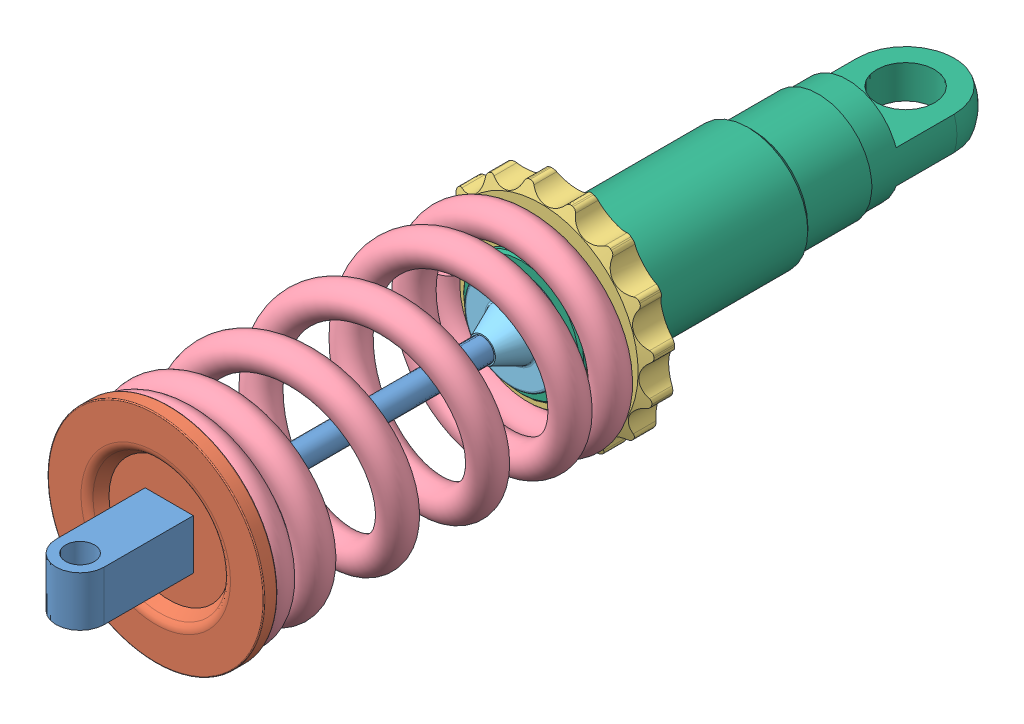
SolidWorks assembly suspension, configuration Default. Lengths in mm.
Overall size (24.15 24.15 93.48).
6 component instances, 6 part files, 38 mates.
Components (placement in the parent):
- Steblo-1: Steblo [Default] at (-24.7525 22.657 64.8138) x (-1 0 0) z (0 1 0) size (5 44.25 5.17)
- shaiba-1: shaiba [Default] at (-24.7525 21.7945 55.5638) x (0.996888 0.07883 0) z (0.07883 -0.996888 0) size (22.45 2.8 22.45)
- gaika-1: gaika [Default] at (-24.7525 21.7945 26.718) x (0.998753 -0.049919 0) z (-0.049919 -0.998753 0) size (22.31 5.02 22.31)
- Prujina-1: Prujina [Default] at (-25.0887 21.6429 17.0138) size (22.62 22.35 41.82)
- Manshon-3: Manshon [Default] at (-24.7525 21.7945 24.8648) x (0.406607 0.913603 0) z (0.913603 -0.406607 0) size (10 4.03 10)
- Cilinder-2: Cilinder [Default] at (-24.7525 21.7945 -26.1618) size (12.45 12.45 45.2)
Mates (geometry in assembly coordinates):
- Concentric1: concentric aligned: cylinder of Cilinder-1 through (-24.6568 29.4468 -39.4946) axis (0 0 1) radius 5; cylinder of Steblo-1 through (-24.7525 21.7945 23.0638) axis (0 0 1) radius 1.203
- Concentric3: concentric aligned: cylinder of Cilinder-1 through (-24.6568 29.4468 -39.4946) axis (0 0 1) radius 5; cylinder of Manshon-1 through (-24.6568 29.4468 33.4722) axis (0 0 1) radius 5
- Coincident1: coincident aligned: plane of Cilinder-1 through (-24.6568 29.4468 -6.9946) normal (0 0 1); plane of Manshon-1 through (-19.9068 29.4468 -6.9946) normal (0 0 1)
- Coincident2: coincident anti-aligned: plane of Steblo-1 through (-22.2525 19.207 55.5638) normal (0 0 -1); plane of shaiba-1 through (-22.2603 21.9916 55.5638) normal (0 0 1)
- Concentric4: concentric aligned: cylinder of Steblo-1 through (-24.7525 21.7945 23.0638) axis (0 0 1) radius 1.203; cylinder of shaiba-1 through (-24.7525 21.7945 67.1029) axis (0 0 1) radius 2.5
- Concentric5: concentric anti-aligned: cylinder of Cilinder-1 through (-24.6568 29.4468 -6.9946) axis (0 0 -1) radius 6.225; cylinder of gaika-1 through (-24.7525 21.7945 68.5253) axis (0 0 1) radius 5.875
- Coincident3: coincident aligned: plane of Cilinder-1 through (-24.6568 29.4468 -52.1946) normal (0 1 0); plane of Prujina-1 through (-25.0887 21.6429 17.0138) normal (0 1 0)
- Coincident4: coincident aligned: plane of Cilinder-1 through (-24.6568 29.4468 -52.1946) normal (1 0 0); plane of Prujina-1 through (-25.0887 21.6429 17.0138) normal (1 0 0)
- Coincident5: coincident anti-aligned: plane of shaiba-1 through (-16.8189 22.4219 55.5638) normal (0 0 -1); plane of Prujina-1 through (-36.1151 -3.957 55.5638) normal (0 0 1)
- Coincident6: coincident anti-aligned: plane of gaika-1 through (-17.6364 21.4389 17.0138) normal (0 0 1); plane of Prujina-1 through (-36.1151 50.6797 17.0138) normal (0 0 -1)
- Concentric6: concentric anti-aligned: cylinder of ? through (-24.6568 -16.8282 -46.8696) axis (0 1 0) radius 3; cylinder of ? through (-24.6568 32.9718 -46.8696) axis (0 -1 0) radius 3
- Coincident7: coincident anti-aligned: plane of ? through (23.3432 31.1718 -54.4198) normal (0 1 0); plane of ? through (-24.6568 36.3468 -41.5446) normal (0 -1 0)
- Concentric7: concentric: cylinder of ? through (-24.6568 32.9718 -46.8696) axis (0 -1 0) radius 2.5; cylinder of ? through (-24.6568 25.9218 -46.8696) axis (0 1 0) radius 3
- Coincident8: coincident anti-aligned: plane of ? through (23.3432 27.7218 -54.4198) normal (0 -1 0); plane of ? through (-24.6568 22.5468 -41.5446) normal (0 1 0)
- Concentric8: concentric aligned: cylinder of Steblo-1 through (-24.7525 19.207 64.8138) axis (0 -1 0) radius 1.5; cylinder of plastmasova vtulka-3 through (-24.6568 32.9718 47.6054) axis (0 -1 0) radius 3
- Coincident9: coincident anti-aligned: plane of Steblo-1 through (-24.7525 24.382 64.8138) normal (0 1 0); plane of ? through (-24.6568 36.3468 103.4554) normal (0 -1 0)
- Concentric9: concentric anti-aligned: cylinder of Steblo-1 through (-24.7525 19.207 64.8138) axis (0 -1 0) radius 1.5; cylinder of plastmasova vtulka-4 through (-24.6568 25.9218 47.6054) axis (0 1 0) radius 3
- Coincident10: coincident anti-aligned: plane of Steblo-1 through (-24.7525 19.207 64.8138) normal (0 -1 0); plane of ? through (-24.6568 22.5468 103.4554) normal (0 1 0)
- Concentric10: concentric anti-aligned: cylinder of plastmasova vtulka-2 through (-24.6568 25.9218 -46.8696) axis (0 1 0) radius 2.5; cylinder of Vtulka na ushite-2 through (-24.6568 29.6968 -46.8696) axis (0 -1 0) radius 2.5
- Coincident11: coincident: plane of ? through (-24.6568 17.5468 -41.5446) normal (0 -1 0); plane of ? through (-24.6568 17.5468 -41.5446) normal (0 -1 0)
- Concentric11: concentric anti-aligned: cylinder of plastmasova vtulka-3 through (-24.6568 32.9718 47.6054) axis (0 -1 0) radius 2.5; cylinder of Vtulka na ushite-1 through (-24.6568 29.1968 47.6054) axis (0 1 0) radius 2.5
- Coincident12: coincident: plane of ? through (-24.6568 41.3468 103.4554) normal (0 1 0); plane of ? through (-24.6568 41.3468 103.4554) normal (0 1 0)
- Concentric13: concentric anti-aligned: cylinder of fasonna gaika-2 through (-24.6568 44.1968 47.6054) axis (0 -1 0) radius 3.9; cylinder of fasonen bolt-2 through (-24.6568 14.6968 47.6054) axis (0 1 0) radius 3
- Coincident15: coincident anti-aligned: plane of fasonna gaika-2 through (-24.6568 14.6968 47.6054) normal (0 -1 0); plane of fasonen bolt-2 through (-24.6568 14.6968 47.6054) normal (0 1 0)
- Concentric14: concentric anti-aligned: cylinder of fasonen bolt-1 through (-24.6568 44.1968 -46.8696) axis (0 -1 0) radius 3; cylinder of fasonna gaika-1 through (-24.6568 14.6968 -46.8696) axis (0 1 0) radius 3.9
- Coincident16: coincident anti-aligned: plane of fasonen bolt-1 through (-24.6568 44.1968 -46.8696) normal (0 -1 0); plane of fasonna gaika-1 through (-24.6568 44.1968 -46.8696) normal (0 1 0)
- Concentric15: concentric anti-aligned: cylinder of Vtulka na ushite-2 through (-24.6568 29.6968 -46.8696) axis (0 -1 0) radius 2; cylinder of fasonna gaika-1 through (-24.6568 14.6968 -46.8696) axis (0 1 0) radius 3.9
- Concentric16: concentric anti-aligned: cylinder of Vtulka na ushite-1 through (-24.6568 29.1968 47.6054) axis (0 1 0) radius 2; cylinder of fasonna gaika-2 through (-24.6568 44.1968 47.6054) axis (0 -1 0) radius 3.9
- Distance3: distance = 2.85 mm anti-aligned: plane of ? through (-24.6568 44.1968 47.6054) normal (0 -1 0); plane of ? through (-24.6568 41.3468 103.4554) normal (0 1 0)
- Distance4: distance = 2.85 mm: plane of ? through (-24.6568 17.5468 -41.5446) normal (0 -1 0); plane of ? through (-24.6568 14.6968 -41.5446) normal (0 1 0)
- Distance8: distance = 43.95 mm anti-aligned: plane of Cilinder-1 through (-24.6568 29.4468 -6.9946) normal (0 0 1); plane of shaiba-1 through (-22.2603 21.9916 54.1638) normal (0 0 -1)
- Coincident20: coincident anti-aligned: plane of Steblo-1 through (-24.7525 21.7945 23.0638) normal (0 0 -1); plane of Manshon-2 through (-23.4335 29.5837 5.8554) normal (0 0 1)
- Coincident21: coincident anti-aligned: plane of Steblo-1 through (-24.7525 21.7945 23.0638) normal (0 0 -1); plane of Manshon-3 through (-24.2635 22.8933 23.0638) normal (0 0 1)
- Concentric18: concentric aligned: cylinder of Steblo-1 through (-24.7525 21.7945 23.0638) axis (0 0 1) radius 1.203; circle of Manshon-3
- Coincident22: coincident anti-aligned: plane of Manshon-3 through (-22.7703 26.2484 19.0382) normal (0 0 -1); plane of Cilinder-2 through (-24.7525 21.7945 19.0382) normal (0 0 1)
- Concentric19: concentric aligned: cylinder of Manshon-3 through (-24.7525 21.7945 60.505) axis (0 0 1) radius 4.875; cone of Cilinder-2 through (-24.7525 21.7945 19.0382) axis (0 0 1)
- Concentric20: concentric aligned: cylinder of Steblo-1 through (-24.7525 21.7945 23.0638) axis (0 0 1) radius 1.203; cylinder of shaiba-1 through (-24.7525 21.7945 67.1029) axis (0 0 1) radius 2.5
- Concentric21: concentric anti-aligned: cylinder of gaika-1 through (-24.7525 21.7945 68.5253) axis (0 0 1) radius 5.875; cylinder of Cilinder-2 through (-24.7525 21.7945 19.0382) axis (0 0 -1) radius 6.225
